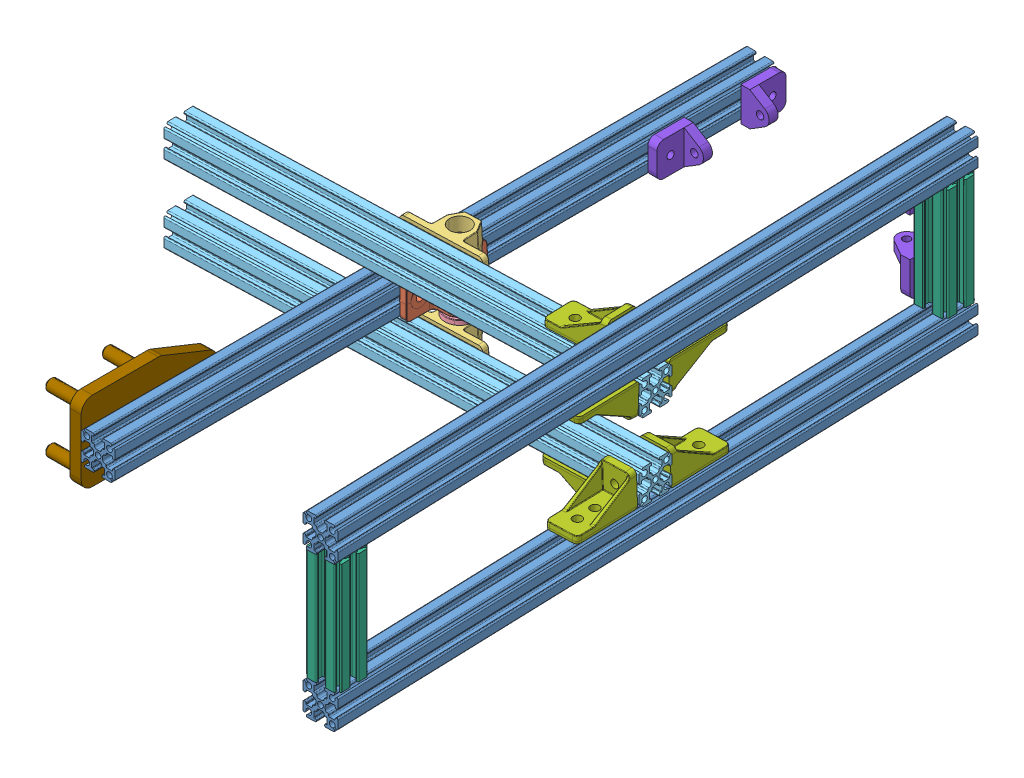
SolidWorks assembly Catapult, configuration Default. Lengths in mm.
Overall size (208.06 79 306.6).
23 component instances, 9 part files, 78 mates.
Components (placement in the parent):
- 12InchRev-1: 12InchRev [Default] at (79.8915 162.4931 -65.6948) size (15 15 292.1)
- REV-41-1316.step-1: REV-41-1316.step [Default] at (95.8915 162.4931 235.213) x (0 0 1) z (0 1 0) size (36 15.01 15.1)
- REV-41-1317.step-1: REV-41-1317.step [Default] at (95.8915 145.4931 235.213) x (0.999467 0 -0.03263) z (0 1 0) size (36 16.01 15.1)
- REV-41-1329.step-2: REV-41-1329.step [Default] at (95.8915 152.9931 235.213) x (0.866025 0 -0.5) z (0 1 0) size (13 13 11)
- 8 inch REV-1: 8 inch REV [Default] at (436.2179 145.4931 240.1107) x (0.03263 0 0.999467) z (-0.999467 0 0.03263) size (15 15 203.2)
- REV-41-1329.step-3: REV-41-1329.step [Default] at (95.8915 171.9931 235.213) x (0.451538 0 0.892252) z (0 -1 0) size (13 13 11)
- 8 inch REV-2: 8 inch REV [Default] at (-249.2169 179.4931 262.4884) x (0.03263 0 0.999467) z (0.999467 0 -0.03263) size (15 15 203.2)
- REV-41-1317.step-2: REV-41-1317.step [Default] at (95.8915 179.4931 235.213) x (-0.999467 0 0.03263) z (0 -1 0) size (36 16.01 15.1)
- 12InchRev-2: 12InchRev [Default] at (177.7746 194.4931 -51.2048) x (0.999467 0 -0.03263) z (0.03263 0 0.999467) size (15 15 292.1)
- 12InchRev-3: 12InchRev [Default] at (177.7746 130.4931 -51.2048) x (0.999467 0 -0.03263) z (0.03263 0 0.999467) size (15 15 292.1)
- 19mmRev-1: 19mmRev [Default] at (192.034 -257.5069 385.5625) x (0.999467 0 -0.03263) z (0 1 0) size (15 15 49)
- 19mmRev-2: 19mmRev [Default] at (182.9922 -257.5069 108.6101) x (0.999467 0 -0.03263) z (0 1 0) size (15 15 49)
- REV-41-1321.step-1: REV-41-1321.step [Default] at (187.6614 137.9931 255.7295) x (0 1 0) z (0.999467 0 -0.03263) size (15.51 27.51 13.94)
- REV-41-1321.step-2: REV-41-1321.step [Default] at (188.3204 186.9931 255.708) x (0 -1 0) z (-0.999467 0 0.03263) size (15.51 27.51 13.94)
- REV-41-1321.step-3: REV-41-1321.step [Default] at (187.508 137.9931 240.7265) x (0 1 0) z (-0.999467 0 0.03263) size (15.51 27.51 13.94)
- REV-41-1321.step-4: REV-41-1321.step [Default] at (186.8804 186.9931 240.747) x (0 -1 0) z (0.999467 0 -0.03263) size (15.51 27.51 13.94)
- REV-41-1321.step-5: REV-41-1321.step [Default] at (180.064 137.9931 248.7673) x (0 -1 0) z (-0.03263 0 -0.999467) size (15.51 27.51 13.94)
- REV-41-1321.step-6: REV-41-1321.step [Default] at (180.0327 186.9931 247.8089) x (0 1 0) z (0.03263 0 0.999467) size (15.51 27.51 13.94)
- SpringHolder-1: SpringHolder [Default] at (175.4962 163.9931 108.8548) x (0 1 0) z (-0.999467 0 0.03263) size (16 15 12.5)
- SpringHolder-2: SpringHolder [Default] at (175.4962 160.9931 108.8548) x (0 -1 0) z (-0.999467 0 0.03263) size (16 15 12.5)
- SpringHolder-5: SpringHolder [Default] at (87.3915 162.4931 112.7052) x (0 0 1) z (1 0 0) size (16 15 12.5)
- SpringHolder-6: SpringHolder [Default] at (87.3915 162.4931 117.7052) x (0 0 -1) z (1 0 0) size (16 15 12.5)
- GolfBall Holder-1: GolfBall Holder [Default] at (72.3915 179.3448 378.8052) x (0 -1 0) z (-1 0 0) size (35 60 19)
Mates (geometry in assembly coordinates):
- Coincident1: coincident: plane of 12InchRev-1 through (87.3915 169.9931 934.3052) normal (1 0 0); plane of REV-41-1316.step-1 through (87.3915 162.4931 217.213) normal (-1 0 0)
- Coincident2: coincident: plane of 12InchRev-1 through (87.3915 154.9931 934.3052) normal (0 -1 0); plane of REV-41-1316.step-1 through (91.297 154.9931 235.213) normal (0 -1 0)
- Concentric1: concentric: cylinder of ? through (95.8915 138.2664 254.9514) axis (0 1 0) radius 4.5; cylinder of REV-41-1317.step-1 through (95.8915 141.2664 254.9514) axis (0 1 0) radius 4.55
- Coincident3: coincident: plane of REV-41-1316.step-1 through (98.3915 162.4931 256.3947) normal (-1 0 0); plane of ? through (98.3915 131.7664 256.3947) normal (-1 0 0)
- Coincident4: coincident: plane of REV-41-1316.step-1 through (95.8915 162.4931 257.8381) normal (-0.5 0 -0.866025); plane of ? through (95.8915 131.7664 257.8381) normal (-0.5 0 -0.866025)
- Coincident5: coincident: plane of ? through (101.3915 133.7664 254.9514) normal (0 1 0); plane of REV-41-1317.step-1 through (91.7652 133.7664 255.1633) normal (0 -1 0)
- Coincident7: coincident: plane of ? through (98.1415 142.7664 254.9514) normal (0 1 0); plane of REV-41-1329.step-2 through (98.2693 142.7664 257.1367) normal (0 -1 0)
- Concentric2: concentric: cylinder of REV-41-1317.step-1 through (95.8915 145.4931 235.213) axis (0 1 0) radius 4.55; cylinder of REV-41-1329.step-2 through (95.8915 148.4931 235.213) axis (0 -1 0) radius 4.5
- Coincident8: coincident: plane of REV-41-1317.step-1 through (96.0263 152.9931 239.3426) normal (0 1 0); plane of REV-41-1329.step-2 through (93.1415 152.9931 230.4499) normal (0 -1 0)
- Coincident9: coincident: plane of REV-41-1316.step-1 through (95.8915 162.4931 238.0998) normal (-0.5 0 -0.866025); plane of REV-41-1329.step-2 through (98.3915 154.9931 236.6564) normal (-0.5 0 -0.866025)
- Coincident10: coincident: plane of REV-41-1316.step-1 through (98.3915 162.4931 236.6564) normal (-1 0 0); plane of REV-41-1329.step-2 through (98.3915 154.9931 233.7696) normal (-1 0 0)
- Coincident11: coincident: plane of REV-41-1317.step-1 through (96.0263 137.9931 239.3426) normal (0 -1 0); plane of 8 inch REV-1 through (-563.0049 137.9931 280.2368) normal (0 -1 0)
- Coincident12: coincident: plane of REV-41-1317.step-1 through (78.1785 145.4931 244.2958) normal (0.03263 0 0.999467); plane of 8 inch REV-1 through (-563.4943 152.9931 265.2448) normal (-0.03263 0 -0.999467)
- Coincident13: coincident: plane of REV-41-1329.step-3 through (90.9841 171.9931 237.6965) normal (0 1 0); plane of REV-41-1317.step-2 through (96.0263 171.9931 239.3426) normal (0 -1 0)
- Concentric3: concentric: cylinder of REV-41-1329.step-3 through (95.8915 176.4931 235.213) axis (0 1 0) radius 4.5; cylinder of REV-41-1317.step-2 through (95.8915 179.4931 235.213) axis (0 -1 0) radius 4.55
- Coincident14: coincident: plane of 8 inch REV-2 through (750.0059 171.9931 222.3624) normal (-0.03263 0 -0.999467); plane of REV-41-1317.step-2 through (114.1593 179.4931 243.1211) normal (0.03263 0 0.999467)
- Coincident15: coincident: plane of 8 inch REV-2 through (750.4953 186.9931 237.3544) normal (0 1 0); plane of REV-41-1317.step-2 through (96.0263 186.9931 239.3426) normal (0 1 0)
- Concentric4: concentric: cylinder of REV-41-1317.step-1 through (95.8915 145.4931 235.213) axis (0 1 0) radius 4.55; cylinder of REV-41-1317.step-2 through (95.8915 179.4931 235.213) axis (0 -1 0) radius 4.55
- Coincident16: coincident: plane of 8 inch REV-1 through (-563.0049 152.9931 280.2368) normal (0.03263 0 0.999467); plane of 8 inch REV-2 through (750.4953 171.9931 237.3544) normal (0.03263 0 0.999467)
- Coincident17: coincident: plane of 8 inch REV-1 through (195.0464 145.4931 247.9844) normal (0.999467 0 -0.03263); plane of 8 inch REV-2 through (195.0464 179.4931 247.9844) normal (0.999467 0 -0.03263)
- Coincident18: coincident: plane of REV-41-1316.step-1 through (91.297 154.9931 235.213) normal (0 -1 0); plane of REV-41-1329.step-2 through (94.2665 154.9931 232.3984) normal (0 1 0)
- Coincident19: coincident: plane of REV-41-1316.step-1 through (91.297 169.9931 235.213) normal (0 1 0); plane of REV-41-1329.step-3 through (92.9917 169.9931 236.6805) normal (0 -1 0)
- Coincident20: coincident: plane of 8 inch REV-2 through (750.4953 186.9931 237.3544) normal (0 1 0); plane of 12InchRev-2 through (217.9007 186.9931 948.018) normal (0 -1 0)
- Coincident21: coincident: plane of 8 inch REV-2 through (195.0464 179.4931 247.9844) normal (0.999467 0 -0.03263); plane of 12InchRev-2 through (217.9007 201.9931 948.018) normal (0.999467 0 -0.03263)
- Coincident22: coincident: plane of 8 inch REV-1 through (195.0464 145.4931 247.9844) normal (0.999467 0 -0.03263); plane of 12InchRev-3 through (217.9007 137.9931 948.018) normal (0.999467 0 -0.03263)
- Coincident23: coincident: plane of 8 inch REV-1 through (-563.0049 137.9931 280.2368) normal (0 -1 0); plane of 12InchRev-3 through (217.9007 137.9931 948.018) normal (0 1 0)
- Coincident24: coincident: plane of 12InchRev-2 through (182.7475 194.4931 101.1141) normal (-0.03263 0 -0.999467); plane of 12InchRev-3 through (182.7475 130.4931 101.1141) normal (-0.03263 0 -0.999467)
- Coincident25: coincident: plane of 12InchRev-3 through (217.9007 137.9931 948.018) normal (0 1 0); plane of 19mmRev-1 through (192.034 137.9931 385.5625) normal (0 -1 0)
- Coincident26: coincident: plane of 12InchRev-2 through (192.2787 194.4931 393.0585) normal (0.03263 0 0.999467); plane of 19mmRev-1 through (199.7747 742.4931 392.8138) normal (0.03263 0 0.999467)
- Coincident27: coincident: plane of 12InchRev-2 through (202.9087 201.9931 948.5075) normal (-0.999467 0 0.03263); plane of 19mmRev-1 through (184.2933 742.4931 378.3113) normal (-0.999467 0 0.03263)
- Coincident28: coincident: plane of 12InchRev-2 through (202.9087 201.9931 948.5075) normal (-0.999467 0 0.03263); plane of 19mmRev-2 through (175.2515 742.4931 101.3588) normal (-0.999467 0 0.03263)
- Coincident29: coincident: plane of 12InchRev-3 through (217.9007 137.9931 948.018) normal (0 1 0); plane of 19mmRev-2 through (182.9922 137.9931 108.6101) normal (0 -1 0)
- Coincident30: coincident: plane of 12InchRev-3 through (182.7475 130.4931 101.1141) normal (-0.03263 0 -0.999467); plane of 19mmRev-2 through (190.2435 742.4931 100.8694) normal (-0.03263 0 -0.999467)
- Coincident31: coincident: plane of 12InchRev-3; plane of ? through (186.4341 134.4542 374.6192) normal (0.999728 0 -0.02331)
- Coincident34: coincident: plane of 12InchRev-2 through (210.7218 186.9931 948.9175) normal (0 -1 0); plane of ? through (179.9291 186.9931 271.764) normal (0 1 0)
- Coincident35: coincident: plane of 8 inch REV-2; plane of ? through (187.0775 179.4931 256.5933) normal (-0.02331 0 -0.999728)
- Coincident36: coincident: plane of 12InchRev-2; plane of ? through (194.9251 171.9931 271.4144) normal (0.999728 0 -0.02331)
- Coincident37: coincident: plane of 12InchRev-3 through (210.7218 137.9931 948.9175) normal (0 1 0); plane of ? through (194.9251 137.9931 271.4144) normal (0 -1 0)
- Coincident38: coincident: plane of 12InchRev-3; plane of ? through (179.9291 137.9931 271.764) normal (-0.999728 0 0.02331)
- Coincident39: coincident: plane of 8 inch REV-1; plane of ? through (187.0775 145.4931 256.5933) normal (-0.02331 0 -0.999728)
- Coincident40: coincident: plane of 12InchRev-3 through (210.7218 137.9931 948.9175) normal (0 1 0); plane of ? through (178.8802 137.9931 226.7763) normal (0 -1 0)
- Coincident41: coincident: plane of 8 inch REV-1; plane of ? through (186.7278 145.4931 241.5974) normal (0.02331 0 0.999728)
- Coincident42: coincident: plane of 12InchRev-3; plane of ? through (178.8802 152.9931 226.7763) normal (-0.999728 0 0.02331)
- Coincident43: coincident: plane of 12InchRev-2; plane of ? through (178.8802 171.9931 226.7763) normal (-0.999728 0 0.02331)
- Coincident45: coincident: plane of 8 inch REV-2; plane of ? through (179.2298 171.9931 241.7722) normal (0.02331 0 0.999728)
- Coincident46: coincident: plane of 12InchRev-2 through (210.7218 186.9931 948.9175) normal (0 -1 0); plane of ? through (186.553 186.9931 234.0994) normal (0 1 0)
- Coincident47: coincident: plane of 12InchRev-3; plane of ? through (179.5795 137.9931 256.7681) normal (0.999728 0 -0.02331)
- Coincident48: coincident: plane of 8 inch REV-1 through (-563.9184 137.9931 274.1036) normal (0 -1 0); plane of ? through (164.5836 137.9931 257.1178) normal (0 1 0)
- Coincident49: coincident: plane of 8 inch REV-1; plane of ? through (171.7319 130.4931 241.947) normal (-0.02331 0 -0.999728)
- Coincident50: coincident: plane of 8 inch REV-2 through (749.9245 186.9931 243.4699) normal (0 1 0); plane of ? through (164.5836 186.9931 257.1178) normal (0 -1 0)
- Coincident51: coincident: plane of 12InchRev-2; plane of ? through (179.4047 194.4931 249.2702) normal (0.999728 0 -0.02331)
- Coincident52: coincident: plane of 8 inch REV-2; plane of ? through (164.2339 186.9931 242.1218) normal (-0.02331 0 -0.999728)
- Coincident53: coincident: plane of 12InchRev-3 through (217.9007 137.9931 948.018) normal (0 1 0); plane of REV-41-1321.step-1 through (188.5588 137.9931 283.2148) normal (0 -1 0)
- Coincident54: coincident: plane of 8 inch REV-1 through (-563.0049 152.9931 280.2368) normal (0.03263 0 0.999467); plane of REV-41-1321.step-1 through (187.6614 137.9931 255.7295) normal (-0.03263 0 -0.999467)
- Coincident59: coincident: plane of 12InchRev-2 through (217.9007 186.9931 948.018) normal (0 -1 0); plane of REV-41-1321.step-2 through (189.2177 186.9931 283.1933) normal (0 1 0)
- Coincident62: coincident: plane of 8 inch REV-2 through (750.4953 171.9931 237.3544) normal (0.03263 0 0.999467); plane of REV-41-1321.step-2 through (188.3204 186.9931 255.708) normal (-0.03263 0 -0.999467)
- Coincident64: coincident: plane of 12InchRev-2 through (217.9007 186.9931 948.018) normal (0 -1 0); plane of REV-41-1321.step-4 through (185.9831 186.9931 213.2616) normal (0 1 0)
- Coincident65: coincident: plane of 8 inch REV-2 through (750.0059 171.9931 222.3624) normal (-0.03263 0 -0.999467); plane of REV-41-1321.step-4 through (186.8804 186.9931 240.747) normal (0.03263 0 0.999467)
- Coincident66: coincident: plane of 8 inch REV-1 through (-563.4943 152.9931 265.2448) normal (-0.03263 0 -0.999467); plane of REV-41-1321.step-3 through (187.508 137.9931 240.7265) normal (0.03263 0 0.999467)
- Coincident67: coincident: plane of 12InchRev-3 through (217.9007 137.9931 948.018) normal (0 1 0); plane of REV-41-1321.step-3 through (186.6107 137.9931 213.2411) normal (0 -1 0)
- Coincident70: coincident: plane of 12InchRev-2 through (202.9087 201.9931 948.5075) normal (-0.999467 0 0.03263); plane of REV-41-1321.step-6 through (180.0327 186.9931 247.8089) normal (0.999467 0 -0.03263)
- Coincident71: coincident: plane of 8 inch REV-2 through (750.4953 186.9931 237.3544) normal (0 1 0); plane of REV-41-1321.step-6 through (152.5473 186.9931 248.7063) normal (0 -1 0)
- Coincident72: coincident: plane of 8 inch REV-1 through (-563.0049 137.9931 280.2368) normal (0 -1 0); plane of REV-41-1321.step-5 through (152.5786 137.9931 249.6646) normal (0 1 0)
- Coincident73: coincident: plane of 12InchRev-3 through (202.9087 137.9931 948.5075) normal (-0.999467 0 0.03263); plane of REV-41-1321.step-5 through (180.064 137.9931 248.7673) normal (0.999467 0 -0.03263)
- Coincident75: coincident: plane of 19mmRev-2 through (175.2515 742.4931 101.3588) normal (-0.999467 0 0.03263); plane of SpringHolder-1 through (175.4962 163.9931 108.8548) normal (0.999467 0 -0.03263)
- Coincident78: coincident: plane of 19mmRev-2 through (190.7329 742.4931 115.8614) normal (0.03263 0 0.999467); plane of SpringHolder-1 through (171.743 177.9931 116.4813) normal (0.03263 0 0.999467)
- Coincident79: coincident: plane of 12InchRev-2 through (202.9087 201.9931 948.5075) normal (-0.999467 0 0.03263); plane of SpringHolder-2 through (175.4962 160.9931 108.8548) normal (0.999467 0 -0.03263)
- Coincident80: coincident: plane of 19mmRev-2 through (190.7329 742.4931 115.8614) normal (0.03263 0 0.999467); plane of SpringHolder-2 through (171.743 146.9931 116.4813) normal (0.03263 0 0.999467)
- Coincident81: coincident: plane of 12InchRev-2 through (217.9007 186.9931 948.018) normal (0 -1 0); plane of SpringHolder-2 through (152.0544 186.9931 102.1161) normal (0 1 0)
- Coincident82: coincident: plane of 12InchRev-3 through (217.9007 137.9931 948.018) normal (0 1 0); plane of SpringHolder-1 through (152.5439 137.9931 117.1081) normal (0 -1 0)
- Coincident83: coincident: plane of 12InchRev-1 through (87.3915 169.9931 934.3052) normal (1 0 0); plane of SpringHolder-5 through (87.3915 162.4931 112.7052) normal (-1 0 0)
- Coincident85: coincident: plane of 12InchRev-1 through (79.8915 162.4931 86.7052) normal (0 0 -1); plane of SpringHolder-5 through (110.6009 169.9931 86.7052) normal (0 0 -1)
- Coincident86: coincident: plane of 12InchRev-1 through (87.3915 154.9931 934.3052) normal (0 -1 0); plane of SpringHolder-5 through (91.3915 154.9931 126.7052) normal (0 -1 0)
- Coincident87: coincident: plane of 12InchRev-1 through (87.3915 169.9931 934.3052) normal (1 0 0); plane of SpringHolder-6 through (87.3915 162.4931 117.7052) normal (-1 0 0)
- Coincident88: coincident: plane of SpringHolder-5 through (91.3915 169.9931 126.7052) normal (0 1 0); plane of SpringHolder-6 through (91.3915 169.9931 103.7052) normal (0 1 0)
- Distance1: distance = 25 mm: plane of SpringHolder-5 through (87.3915 162.4931 102.7052) normal (0 0 1); plane of SpringHolder-6 through (87.3915 162.4931 127.7052) normal (0 0 -1)
- Coincident90: coincident: plane of 12InchRev-1 through (79.8915 162.4931 378.8052) normal (0 0 1); plane of GolfBall Holder-1 through (67.3915 179.3448 378.8052) normal (0 0 1)
- Coincident91: coincident: plane of 12InchRev-1 through (72.3915 169.9931 934.3052) normal (-1 0 0); plane of GolfBall Holder-1 through (72.3915 179.3448 378.8052) normal (1 0 0)
